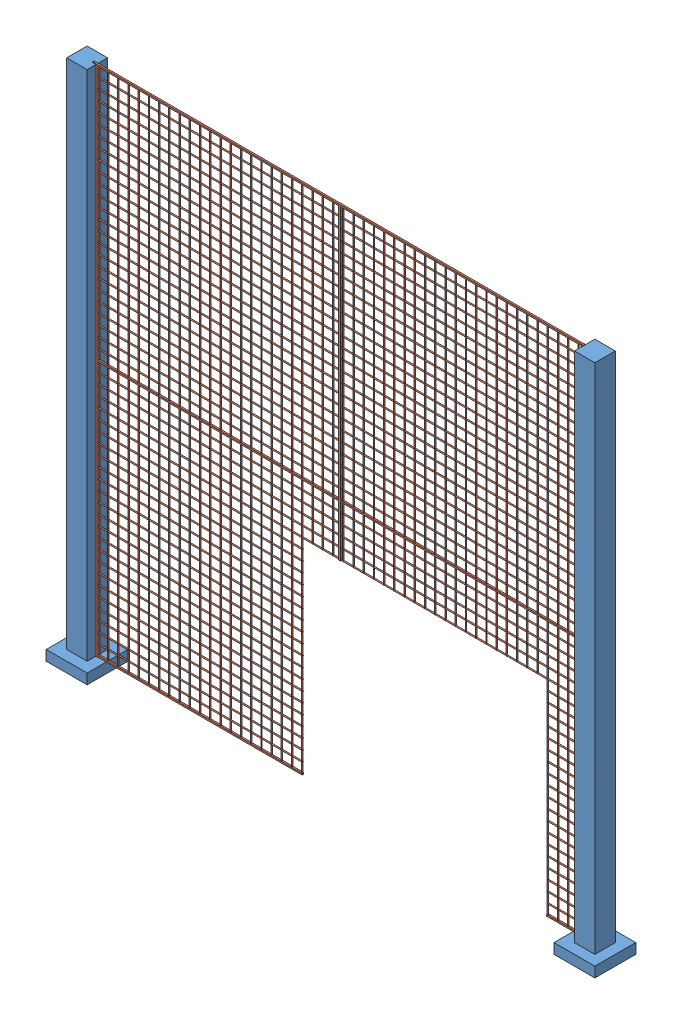
SolidWorks assembly bariera_2m, configuration Default. Lengths in mm.
Overall size (2682.5 2557.5 200).
3 component instances, 2 part files, 11 mates.
Components (placement in the parent):
- palo_barriera-1: palo_barriera [Default] at origin size (200 2555 200)
- palo_barriera-2: palo_barriera [Default] at (2482.5 0 0) size (200 2555 200)
- rete_2m-1: rete_2m [Default] at (2405 2553.75 2.5) x (-1 0 0) z (0 -1 0) size (2400 10 2507.5)
Mates (geometry in assembly coordinates):
- Coincidente1: coordinate: point of palo_barriera-1
- Distanza2: distance = 50 mm: cylinder of rete_1m-1 through (2405 53.75 2.5) axis (0 1 0) radius 2.5; plane of palo_barriera-1 through (-50 2550 50) normal (0 0 1)
- Coincidente5: coincident anti-aligned: plane of rete_1m-1 through (1950 52.5 2.5) normal (1 0 0); plane of rete_1m-2 through (1950 2552.5 2.5) normal (-1 0 0)
- Concentrico1: concentric anti-aligned: cylinder of rete_1m-1 through (1040 2552.5 2.5) axis (-1 0 0) radius 2.5; cylinder of rete_1m-2 through (1040 2552.5 2.5) axis (1 0 0) radius 2.5
- Concentrico2: concentric anti-aligned: cylinder of rete_1m-1 through (1040 52.5 2.5) axis (-1 0 0) radius 2.5; cylinder of rete_1m-2 through (1040 52.5 2.5) axis (1 0 0) radius 2.5
- Coincidente9: coincident aligned: plane of palo_barriera-1 through (-50 2550 50) normal (0 0 1); plane of palo_barriera-2 through (2432.5 2550 50) normal (0 0 1)
- Coincidente10: coincident aligned: plane of palo_barriera-1 through (0 2555 0) normal (0 1 0); plane of palo_barriera-2 through (2482.5 2555 0) normal (0 1 0)
- Coincidente12: coincident aligned: plane of palo_barriera-2 through (1950 2550 -50) normal (-1 0 0); circle of rete_1m-2
- Coincidente14: coincident anti-aligned: plane of palo_barriera-2 through (2432.5 2550 -50) normal (-1 0 0); plane of rete_2m-1 through (2432.5 2553.75 2.5) normal (1 0 0)
- Coincidente15: coincident anti-aligned: plane of palo_barriera-1 through (50 2550 -50) normal (1 0 0); plane of rete_2m-1 through (50 35.8579 7.5) normal (-1 0 0)
- Coincidente16: coincident anti-aligned: plane of palo_barriera-1 through (100 50 100) normal (0 1 0); plane of rete_2m-1 through (21.8934 50 -1.25) normal (0 -1 0)
